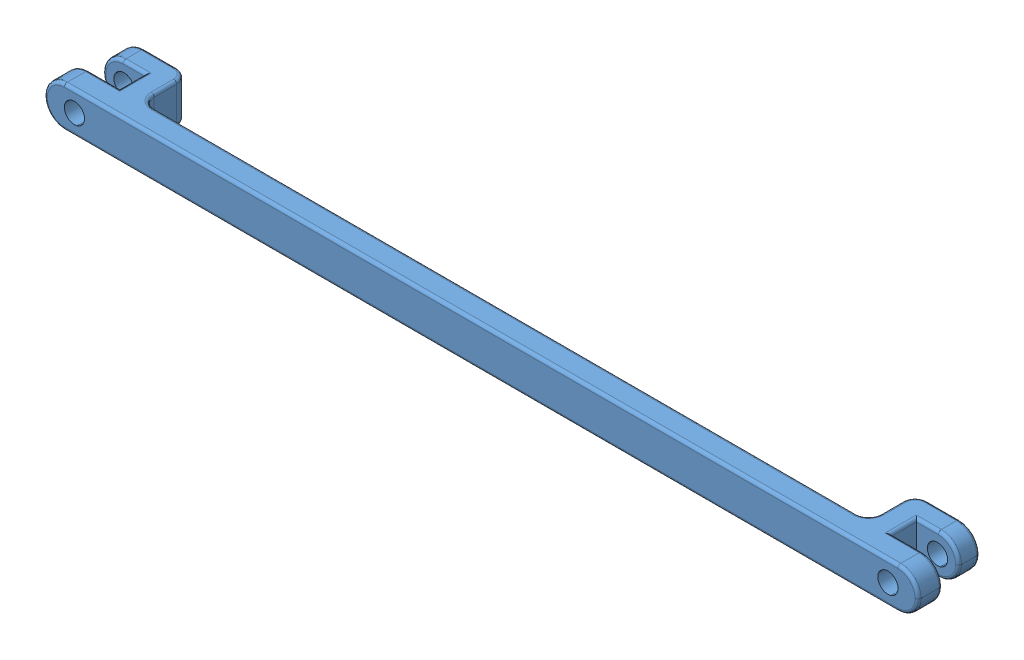
SolidWorks assembly duma_khung_gam_lan_cuoi, configuration Default. Lengths in mm.
Overall size (1446 67 256.41).
2 component instances, 1 part files, 0 mates.
Components (placement in the parent):
- khung_gam_lan3-1: khung_gam_lan3 [Default] at (-9.0622 -43.5126 13.2383) size (1446 67 256.41)
  - KHUNG GẦM-1: KHUNG GẦM [Default] at (535.6524 816.3437 1126.9922) size (1446 67 117)
